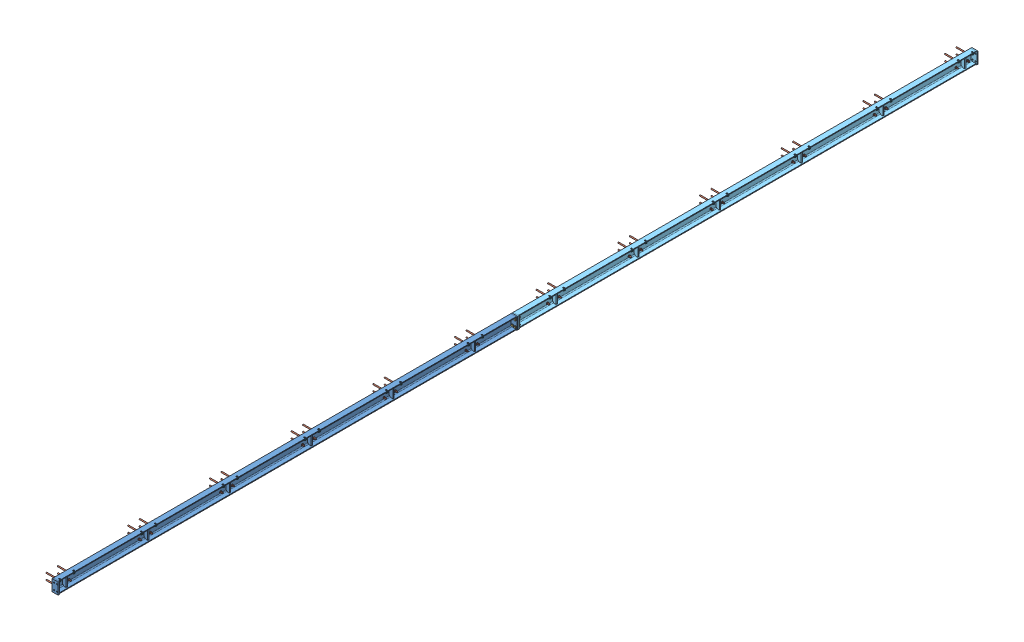
SolidWorks assembly 0405-WALL ASSEMBLAGE, configuration Predeterminado. Lengths in mm.
Overall size (203.98 166 11260).
106 component instances, 7 part files, 35 mates.
Components (placement in the parent):
- 0418-WALL SUPPORT-1: 0418-WALL SUPPORT [Predeterminado] at (-23.835 3.2677 -2786.25) size (75 140 5630)
- M-12x160 CHEMICAL ANCHOR-1: M-12x160 CHEMICAL ANCHOR [DIN 525 - M20 x 210 --- 75N] at (-150.835 41.2677 2769.75) x (1 0 0) z (0 -0.732552 0.680711) size (160 24 24)
- M-12x160 CHEMICAL ANCHOR-31: M-12x160 CHEMICAL ANCHOR [DIN 525 - M20 x 210 --- 75N] at (-150.835 -34.7323 2769.75) x (1 0 0) z (0 -0.732552 0.680711) size (160 24 24)
- M-12x160 CHEMICAL ANCHOR-49: M-12x160 CHEMICAL ANCHOR [DIN 525 - M20 x 210 --- 75N] at (-150.835 41.2677 2629.75) x (1 0 0) z (0 -0.732552 0.680711) size (160 24 24)
- M-12x160 CHEMICAL ANCHOR-61: M-12x160 CHEMICAL ANCHOR [DIN 525 - M20 x 210 --- 75N] at (-150.835 -34.7323 2629.75) x (1 0 0) z (0 -0.732552 0.680711) size (160 24 24)
- M-12x160 CHEMICAL ANCHOR-32: M-12x160 CHEMICAL ANCHOR [DIN 525 - M20 x 210 --- 75N] at (-150.835 -34.7323 1769.75) x (1 0 0) z (0 -0.732552 0.680711) size (160 24 24)
- M-12x160 CHEMICAL ANCHOR-33: M-12x160 CHEMICAL ANCHOR [DIN 525 - M20 x 210 --- 75N] at (-150.835 -34.7323 769.75) x (1 0 0) z (0 -0.732552 0.680711) size (160 24 24)
- M-12x160 CHEMICAL ANCHOR-34: M-12x160 CHEMICAL ANCHOR [DIN 525 - M20 x 210 --- 75N] at (-150.835 -34.7323 -230.25) x (1 0 0) z (0 -0.732552 0.680711) size (160 24 24)
- M-12x160 CHEMICAL ANCHOR-35: M-12x160 CHEMICAL ANCHOR [DIN 525 - M20 x 210 --- 75N] at (-150.835 -34.7323 -1230.25) x (1 0 0) z (0 -0.732552 0.680711) size (160 24 24)
- M-12x160 CHEMICAL ANCHOR-36: M-12x160 CHEMICAL ANCHOR [DIN 525 - M20 x 210 --- 75N] at (-150.835 -34.7323 -2230.25) x (1 0 0) z (0 -0.732552 0.680711) size (160 24 24)
- M-12x160 CHEMICAL ANCHOR-62: M-12x160 CHEMICAL ANCHOR [DIN 525 - M20 x 210 --- 75N] at (-150.835 -34.7323 1629.75) x (1 0 0) z (0 -0.732552 0.680711) size (160 24 24)
- M-12x160 CHEMICAL ANCHOR-63: M-12x160 CHEMICAL ANCHOR [DIN 525 - M20 x 210 --- 75N] at (-150.835 -34.7323 629.75) x (1 0 0) z (0 -0.732552 0.680711) size (160 24 24)
- M-12x160 CHEMICAL ANCHOR-64: M-12x160 CHEMICAL ANCHOR [DIN 525 - M20 x 210 --- 75N] at (-150.835 -34.7323 -370.25) x (1 0 0) z (0 -0.732552 0.680711) size (160 24 24)
- M-12x160 CHEMICAL ANCHOR-65: M-12x160 CHEMICAL ANCHOR [DIN 525 - M20 x 210 --- 75N] at (-150.835 -34.7323 -1370.25) x (1 0 0) z (0 -0.732552 0.680711) size (160 24 24)
- M-12x160 CHEMICAL ANCHOR-66: M-12x160 CHEMICAL ANCHOR [DIN 525 - M20 x 210 --- 75N] at (-150.835 -34.7323 -2370.25) x (1 0 0) z (0 -0.732552 0.680711) size (160 24 24)
- M-12x160 CHEMICAL ANCHOR-50: M-12x160 CHEMICAL ANCHOR [DIN 525 - M20 x 210 --- 75N] at (-150.835 41.2677 1629.75) x (1 0 0) z (0 -0.732552 0.680711) size (160 24 24)
- M-12x160 CHEMICAL ANCHOR-51: M-12x160 CHEMICAL ANCHOR [DIN 525 - M20 x 210 --- 75N] at (-150.835 41.2677 629.75) x (1 0 0) z (0 -0.732552 0.680711) size (160 24 24)
- M-12x160 CHEMICAL ANCHOR-52: M-12x160 CHEMICAL ANCHOR [DIN 525 - M20 x 210 --- 75N] at (-150.835 41.2677 -370.25) x (1 0 0) z (0 -0.732552 0.680711) size (160 24 24)
- M-12x160 CHEMICAL ANCHOR-53: M-12x160 CHEMICAL ANCHOR [DIN 525 - M20 x 210 --- 75N] at (-150.835 41.2677 -1370.25) x (1 0 0) z (0 -0.732552 0.680711) size (160 24 24)
- M-12x160 CHEMICAL ANCHOR-54: M-12x160 CHEMICAL ANCHOR [DIN 525 - M20 x 210 --- 75N] at (-150.835 41.2677 -2370.25) x (1 0 0) z (0 -0.732552 0.680711) size (160 24 24)
- M-12x160 CHEMICAL ANCHOR-20: M-12x160 CHEMICAL ANCHOR [DIN 525 - M20 x 210 --- 75N] at (-150.835 41.2677 1769.75) x (1 0 0) z (0 -0.732552 0.680711) size (160 24 24)
- M-12x160 CHEMICAL ANCHOR-21: M-12x160 CHEMICAL ANCHOR [DIN 525 - M20 x 210 --- 75N] at (-150.835 41.2677 769.75) x (1 0 0) z (0 -0.732552 0.680711) size (160 24 24)
- M-12x160 CHEMICAL ANCHOR-22: M-12x160 CHEMICAL ANCHOR [DIN 525 - M20 x 210 --- 75N] at (-150.835 41.2677 -230.25) x (1 0 0) z (0 -0.732552 0.680711) size (160 24 24)
- M-12x160 CHEMICAL ANCHOR-23: M-12x160 CHEMICAL ANCHOR [DIN 525 - M20 x 210 --- 75N] at (-150.835 41.2677 -1230.25) x (1 0 0) z (0 -0.732552 0.680711) size (160 24 24)
- M-12x160 CHEMICAL ANCHOR-24: M-12x160 CHEMICAL ANCHOR [DIN 525 - M20 x 210 --- 75N] at (-150.835 41.2677 -2230.25) x (1 0 0) z (0 -0.732552 0.680711) size (160 24 24)
- M-12x55 DIN-6914-18 and DIN-6916-1: M-12x55 DIN-6914-18 and DIN-6916 [DIN 6914 - M12 x 35 x 21-N] at (1.165 43.2677 -2776.25) x (0 0 -1) z (0.381849 -0.924225 0) size (63 26 26)
- M-12x55 DIN-6914-18 and DIN-6916-2: M-12x55 DIN-6914-18 and DIN-6916 [DIN 6914 - M12 x 35 x 21-N] at (36.165 43.2677 -2776.25) x (0 0 -1) z (0.381849 -0.924225 0) size (63 26 26)
- M-12x55 DIN-6914-18 and DIN-6916-3: M-12x55 DIN-6914-18 and DIN-6916 [DIN 6914 - M12 x 35 x 21-N] at (1.165 -36.7323 -2776.25) x (0 0 -1) z (0.381849 -0.924225 0) size (63 26 26)
- M-12x55 DIN-6914-18 and DIN-6916-4: M-12x55 DIN-6914-18 and DIN-6916 [DIN 6914 - M12 x 35 x 21-N] at (36.165 -36.7323 -2776.25) x (0 0 -1) z (0.381849 -0.924225 0) size (63 26 26)
- M-12 DIN-6915 and DIN-6916-1: M-12 DIN-6915 and DIN-6916 [Hexagon Nut DIN 6915 - M12 - N] at (1.165 43.2677 -2818.25) size (26 26 12)
- M-12 DIN-6915 and DIN-6916-2: M-12 DIN-6915 and DIN-6916 [Hexagon Nut DIN 6915 - M12 - N] at (36.165 43.2677 -2818.25) size (26 26 12)
- M-12 DIN-6915 and DIN-6916-3: M-12 DIN-6915 and DIN-6916 [Hexagon Nut DIN 6915 - M12 - N] at (36.165 -36.7323 -2818.25) size (26 26 12)
- M-12 DIN-6915 and DIN-6916-4: M-12 DIN-6915 and DIN-6916 [Hexagon Nut DIN 6915 - M12 - N] at (1.165 -36.7323 -2818.25) size (26 26 12)
- 0419-WALL SUPPORT-1: 0419-WALL SUPPORT [Predeterminado] at (-23.835 3.2677 -2816.25) x (1 0 0) z (0 0 -1) size (75 140 5630)
- M-12x160 CHEMICAL ANCHOR-25: M-12x160 CHEMICAL ANCHOR [DIN 525 - M20 x 210 --- 75N] at (-150.835 41.2677 -3230.25) x (1 0 0) z (0 -0.732552 0.680711) size (160 24 24)
- M-12x160 CHEMICAL ANCHOR-26: M-12x160 CHEMICAL ANCHOR [DIN 525 - M20 x 210 --- 75N] at (-150.835 41.2677 -4230.25) x (1 0 0) z (0 -0.732552 0.680711) size (160 24 24)
- M-12x160 CHEMICAL ANCHOR-27: M-12x160 CHEMICAL ANCHOR [DIN 525 - M20 x 210 --- 75N] at (-150.835 41.2677 -5230.25) x (1 0 0) z (0 -0.732552 0.680711) size (160 24 24)
- M-12x160 CHEMICAL ANCHOR-28: M-12x160 CHEMICAL ANCHOR [DIN 525 - M20 x 210 --- 75N] at (-150.835 41.2677 -6230.25) x (1 0 0) z (0 -0.732552 0.680711) size (160 24 24)
- M-12x160 CHEMICAL ANCHOR-29: M-12x160 CHEMICAL ANCHOR [DIN 525 - M20 x 210 --- 75N] at (-150.835 41.2677 -7230.25) x (1 0 0) z (0 -0.732552 0.680711) size (160 24 24)
- M-12x160 CHEMICAL ANCHOR-30: M-12x160 CHEMICAL ANCHOR [DIN 525 - M20 x 210 --- 75N] at (-150.835 41.2677 -8230.25) x (1 0 0) z (0 -0.732552 0.680711) size (160 24 24)
- M-12x160 CHEMICAL ANCHOR-55: M-12x160 CHEMICAL ANCHOR [DIN 525 - M20 x 210 --- 75N] at (-150.835 41.2677 -3370.25) x (1 0 0) z (0 -0.732552 0.680711) size (160 24 24)
- M-12x160 CHEMICAL ANCHOR-56: M-12x160 CHEMICAL ANCHOR [DIN 525 - M20 x 210 --- 75N] at (-150.835 41.2677 -4370.25) x (1 0 0) z (0 -0.732552 0.680711) size (160 24 24)
- M-12x160 CHEMICAL ANCHOR-57: M-12x160 CHEMICAL ANCHOR [DIN 525 - M20 x 210 --- 75N] at (-150.835 41.2677 -5370.25) x (1 0 0) z (0 -0.732552 0.680711) size (160 24 24)
- M-12x160 CHEMICAL ANCHOR-58: M-12x160 CHEMICAL ANCHOR [DIN 525 - M20 x 210 --- 75N] at (-150.835 41.2677 -6370.25) x (1 0 0) z (0 -0.732552 0.680711) size (160 24 24)
- M-12x160 CHEMICAL ANCHOR-59: M-12x160 CHEMICAL ANCHOR [DIN 525 - M20 x 210 --- 75N] at (-150.835 41.2677 -7370.25) x (1 0 0) z (0 -0.732552 0.680711) size (160 24 24)
- M-12x160 CHEMICAL ANCHOR-60: M-12x160 CHEMICAL ANCHOR [DIN 525 - M20 x 210 --- 75N] at (-150.835 41.2677 -8370.25) x (1 0 0) z (0 -0.732552 0.680711) size (160 24 24)
- M-12x160 CHEMICAL ANCHOR-67: M-12x160 CHEMICAL ANCHOR [DIN 525 - M20 x 210 --- 75N] at (-150.835 -34.7323 -3370.25) x (1 0 0) z (0 -0.732552 0.680711) size (160 24 24)
- M-12x160 CHEMICAL ANCHOR-68: M-12x160 CHEMICAL ANCHOR [DIN 525 - M20 x 210 --- 75N] at (-150.835 -34.7323 -4370.25) x (1 0 0) z (0 -0.732552 0.680711) size (160 24 24)
- M-12x160 CHEMICAL ANCHOR-69: M-12x160 CHEMICAL ANCHOR [DIN 525 - M20 x 210 --- 75N] at (-150.835 -34.7323 -5370.25) x (1 0 0) z (0 -0.732552 0.680711) size (160 24 24)
- M-12x160 CHEMICAL ANCHOR-70: M-12x160 CHEMICAL ANCHOR [DIN 525 - M20 x 210 --- 75N] at (-150.835 -34.7323 -6370.25) x (1 0 0) z (0 -0.732552 0.680711) size (160 24 24)
- M-12x160 CHEMICAL ANCHOR-71: M-12x160 CHEMICAL ANCHOR [DIN 525 - M20 x 210 --- 75N] at (-150.835 -34.7323 -7370.25) x (1 0 0) z (0 -0.732552 0.680711) size (160 24 24)
- M-12x160 CHEMICAL ANCHOR-72: M-12x160 CHEMICAL ANCHOR [DIN 525 - M20 x 210 --- 75N] at (-150.835 -34.7323 -8370.25) x (1 0 0) z (0 -0.732552 0.680711) size (160 24 24)
- M-12x160 CHEMICAL ANCHOR-43: M-12x160 CHEMICAL ANCHOR [DIN 525 - M20 x 210 --- 75N] at (-150.835 -34.7323 -3230.25) x (1 0 0) z (0 -0.732552 0.680711) size (160 24 24)
- M-12x160 CHEMICAL ANCHOR-44: M-12x160 CHEMICAL ANCHOR [DIN 525 - M20 x 210 --- 75N] at (-150.835 -34.7323 -4230.25) x (1 0 0) z (0 -0.732552 0.680711) size (160 24 24)
- M-12x160 CHEMICAL ANCHOR-45: M-12x160 CHEMICAL ANCHOR [DIN 525 - M20 x 210 --- 75N] at (-150.835 -34.7323 -5230.25) x (1 0 0) z (0 -0.732552 0.680711) size (160 24 24)
- M-12x160 CHEMICAL ANCHOR-46: M-12x160 CHEMICAL ANCHOR [DIN 525 - M20 x 210 --- 75N] at (-150.835 -34.7323 -6230.25) x (1 0 0) z (0 -0.732552 0.680711) size (160 24 24)
- M-12x160 CHEMICAL ANCHOR-47: M-12x160 CHEMICAL ANCHOR [DIN 525 - M20 x 210 --- 75N] at (-150.835 -34.7323 -7230.25) x (1 0 0) z (0 -0.732552 0.680711) size (160 24 24)
- M-12x160 CHEMICAL ANCHOR-48: M-12x160 CHEMICAL ANCHOR [DIN 525 - M20 x 210 --- 75N] at (-150.835 -34.7323 -8230.25) x (1 0 0) z (0 -0.732552 0.680711) size (160 24 24)
- M-16x45 DIN-6914-18 and DIN-6916-1: M-16x45 DIN-6914-18 and DIN-6916 [DIN 6914 - M20 x 65 x 31-N] at (26.165 99.2677 2785.75) x (0 -1 0) z (0 0 1) size (58 30 30)
- M-16x45 DIN-6914-18 and DIN-6916-25: M-16x45 DIN-6914-18 and DIN-6916 [DIN 6914 - M20 x 65 x 31-N] at (26.165 99.2677 2613.75) x (0 -1 0) z (0 0 1) size (58 30 30)
- M-16 DIN-6915 and DIN-6916-1: M-16 DIN-6915 and DIN-6916 [Hexagon Nut DIN 6915 - M20 - N] at (26.165 61.2677 2785.75) x (1 0 0) z (0 1 0) size (30 30 16)
- M-16 DIN-6915 and DIN-6916-2: M-16 DIN-6915 and DIN-6916 [Hexagon Nut DIN 6915 - M20 - N] at (26.165 61.2677 2613.75) x (1 0 0) z (0 1 0) size (30 30 16)
- M-16 DIN-6915 and DIN-6916-3: M-16 DIN-6915 and DIN-6916 [Hexagon Nut DIN 6915 - M20 - N] at (26.165 61.2677 1785.75) x (1 0 0) z (0 1 0) size (30 30 16)
- M-16 DIN-6915 and DIN-6916-4: M-16 DIN-6915 and DIN-6916 [Hexagon Nut DIN 6915 - M20 - N] at (26.165 61.2677 785.75) x (1 0 0) z (0 1 0) size (30 30 16)
- M-16 DIN-6915 and DIN-6916-5: M-16 DIN-6915 and DIN-6916 [Hexagon Nut DIN 6915 - M20 - N] at (26.165 61.2677 -214.25) x (1 0 0) z (0 1 0) size (30 30 16)
- M-16 DIN-6915 and DIN-6916-6: M-16 DIN-6915 and DIN-6916 [Hexagon Nut DIN 6915 - M20 - N] at (26.165 61.2677 -1214.25) x (1 0 0) z (0 1 0) size (30 30 16)
- M-16 DIN-6915 and DIN-6916-7: M-16 DIN-6915 and DIN-6916 [Hexagon Nut DIN 6915 - M20 - N] at (26.165 61.2677 -2214.25) x (1 0 0) z (0 1 0) size (30 30 16)
- M-16 DIN-6915 and DIN-6916-8: M-16 DIN-6915 and DIN-6916 [Hexagon Nut DIN 6915 - M20 - N] at (26.165 61.2677 -3214.25) x (1 0 0) z (0 1 0) size (30 30 16)
- M-16 DIN-6915 and DIN-6916-9: M-16 DIN-6915 and DIN-6916 [Hexagon Nut DIN 6915 - M20 - N] at (26.165 61.2677 -4214.25) x (1 0 0) z (0 1 0) size (30 30 16)
- M-16 DIN-6915 and DIN-6916-10: M-16 DIN-6915 and DIN-6916 [Hexagon Nut DIN 6915 - M20 - N] at (26.165 61.2677 -5214.25) x (1 0 0) z (0 1 0) size (30 30 16)
- M-16 DIN-6915 and DIN-6916-11: M-16 DIN-6915 and DIN-6916 [Hexagon Nut DIN 6915 - M20 - N] at (26.165 61.2677 -6214.25) x (1 0 0) z (0 1 0) size (30 30 16)
- M-16 DIN-6915 and DIN-6916-12: M-16 DIN-6915 and DIN-6916 [Hexagon Nut DIN 6915 - M20 - N] at (26.165 61.2677 -7214.25) x (1 0 0) z (0 1 0) size (30 30 16)
- M-16 DIN-6915 and DIN-6916-13: M-16 DIN-6915 and DIN-6916 [Hexagon Nut DIN 6915 - M20 - N] at (26.165 61.2677 -8214.25) x (1 0 0) z (0 1 0) size (30 30 16)
- M-16 DIN-6915 and DIN-6916-14: M-16 DIN-6915 and DIN-6916 [Hexagon Nut DIN 6915 - M20 - N] at (26.165 61.2677 1613.75) x (1 0 0) z (0 1 0) size (30 30 16)
- M-16 DIN-6915 and DIN-6916-15: M-16 DIN-6915 and DIN-6916 [Hexagon Nut DIN 6915 - M20 - N] at (26.165 61.2677 613.75) x (1 0 0) z (0 1 0) size (30 30 16)
- M-16 DIN-6915 and DIN-6916-16: M-16 DIN-6915 and DIN-6916 [Hexagon Nut DIN 6915 - M20 - N] at (26.165 61.2677 -386.25) x (1 0 0) z (0 1 0) size (30 30 16)
- M-16 DIN-6915 and DIN-6916-17: M-16 DIN-6915 and DIN-6916 [Hexagon Nut DIN 6915 - M20 - N] at (26.165 61.2677 -1386.25) x (1 0 0) z (0 1 0) size (30 30 16)
- M-16 DIN-6915 and DIN-6916-18: M-16 DIN-6915 and DIN-6916 [Hexagon Nut DIN 6915 - M20 - N] at (26.165 61.2677 -2386.25) x (1 0 0) z (0 1 0) size (30 30 16)
- M-16 DIN-6915 and DIN-6916-19: M-16 DIN-6915 and DIN-6916 [Hexagon Nut DIN 6915 - M20 - N] at (26.165 61.2677 -3386.25) x (1 0 0) z (0 1 0) size (30 30 16)
- M-16 DIN-6915 and DIN-6916-20: M-16 DIN-6915 and DIN-6916 [Hexagon Nut DIN 6915 - M20 - N] at (26.165 61.2677 -4386.25) x (1 0 0) z (0 1 0) size (30 30 16)
- M-16 DIN-6915 and DIN-6916-21: M-16 DIN-6915 and DIN-6916 [Hexagon Nut DIN 6915 - M20 - N] at (26.165 61.2677 -5386.25) x (1 0 0) z (0 1 0) size (30 30 16)
- M-16 DIN-6915 and DIN-6916-22: M-16 DIN-6915 and DIN-6916 [Hexagon Nut DIN 6915 - M20 - N] at (26.165 61.2677 -6386.25) x (1 0 0) z (0 1 0) size (30 30 16)
- M-16 DIN-6915 and DIN-6916-23: M-16 DIN-6915 and DIN-6916 [Hexagon Nut DIN 6915 - M20 - N] at (26.165 61.2677 -7386.25) x (1 0 0) z (0 1 0) size (30 30 16)
- M-16 DIN-6915 and DIN-6916-24: M-16 DIN-6915 and DIN-6916 [Hexagon Nut DIN 6915 - M20 - N] at (26.165 61.2677 -8386.25) x (1 0 0) z (0 1 0) size (30 30 16)
- M-16x45 DIN-6914-18 and DIN-6916-26: M-16x45 DIN-6914-18 and DIN-6916 [DIN 6914 - M20 x 65 x 31-N] at (26.165 99.2677 1613.75) x (0 -1 0) z (0 0 1) size (58 30 30)
- M-16x45 DIN-6914-18 and DIN-6916-27: M-16x45 DIN-6914-18 and DIN-6916 [DIN 6914 - M20 x 65 x 31-N] at (26.165 99.2677 613.75) x (0 -1 0) z (0 0 1) size (58 30 30)
- M-16x45 DIN-6914-18 and DIN-6916-28: M-16x45 DIN-6914-18 and DIN-6916 [DIN 6914 - M20 x 65 x 31-N] at (26.165 99.2677 -386.25) x (0 -1 0) z (0 0 1) size (58 30 30)
- M-16x45 DIN-6914-18 and DIN-6916-29: M-16x45 DIN-6914-18 and DIN-6916 [DIN 6914 - M20 x 65 x 31-N] at (26.165 99.2677 -1386.25) x (0 -1 0) z (0 0 1) size (58 30 30)
- M-16x45 DIN-6914-18 and DIN-6916-30: M-16x45 DIN-6914-18 and DIN-6916 [DIN 6914 - M20 x 65 x 31-N] at (26.165 99.2677 -2386.25) x (0 -1 0) z (0 0 1) size (58 30 30)
- M-16x45 DIN-6914-18 and DIN-6916-31: M-16x45 DIN-6914-18 and DIN-6916 [DIN 6914 - M20 x 65 x 31-N] at (26.165 99.2677 -3386.25) x (0 -1 0) z (0 0 1) size (58 30 30)
- M-16x45 DIN-6914-18 and DIN-6916-32: M-16x45 DIN-6914-18 and DIN-6916 [DIN 6914 - M20 x 65 x 31-N] at (26.165 99.2677 -4386.25) x (0 -1 0) z (0 0 1) size (58 30 30)
- M-16x45 DIN-6914-18 and DIN-6916-33: M-16x45 DIN-6914-18 and DIN-6916 [DIN 6914 - M20 x 65 x 31-N] at (26.165 99.2677 -5386.25) x (0 -1 0) z (0 0 1) size (58 30 30)
- M-16x45 DIN-6914-18 and DIN-6916-34: M-16x45 DIN-6914-18 and DIN-6916 [DIN 6914 - M20 x 65 x 31-N] at (26.165 99.2677 -6386.25) x (0 -1 0) z (0 0 1) size (58 30 30)
- M-16x45 DIN-6914-18 and DIN-6916-35: M-16x45 DIN-6914-18 and DIN-6916 [DIN 6914 - M20 x 65 x 31-N] at (26.165 99.2677 -7386.25) x (0 -1 0) z (0 0 1) size (58 30 30)
- M-16x45 DIN-6914-18 and DIN-6916-36: M-16x45 DIN-6914-18 and DIN-6916 [DIN 6914 - M20 x 65 x 31-N] at (26.165 99.2677 -8386.25) x (0 -1 0) z (0 0 1) size (58 30 30)
- M-16x45 DIN-6914-18 and DIN-6916-14: M-16x45 DIN-6914-18 and DIN-6916 [DIN 6914 - M20 x 65 x 31-N] at (26.165 99.2677 1785.75) x (0 -1 0) z (0 0 1) size (58 30 30)
- M-16x45 DIN-6914-18 and DIN-6916-15: M-16x45 DIN-6914-18 and DIN-6916 [DIN 6914 - M20 x 65 x 31-N] at (26.165 99.2677 785.75) x (0 -1 0) z (0 0 1) size (58 30 30)
- M-16x45 DIN-6914-18 and DIN-6916-16: M-16x45 DIN-6914-18 and DIN-6916 [DIN 6914 - M20 x 65 x 31-N] at (26.165 99.2677 -214.25) x (0 -1 0) z (0 0 1) size (58 30 30)
- M-16x45 DIN-6914-18 and DIN-6916-17: M-16x45 DIN-6914-18 and DIN-6916 [DIN 6914 - M20 x 65 x 31-N] at (26.165 99.2677 -1214.25) x (0 -1 0) z (0 0 1) size (58 30 30)
- M-16x45 DIN-6914-18 and DIN-6916-18: M-16x45 DIN-6914-18 and DIN-6916 [DIN 6914 - M20 x 65 x 31-N] at (26.165 99.2677 -2214.25) x (0 -1 0) z (0 0 1) size (58 30 30)
- M-16x45 DIN-6914-18 and DIN-6916-19: M-16x45 DIN-6914-18 and DIN-6916 [DIN 6914 - M20 x 65 x 31-N] at (26.165 99.2677 -3214.25) x (0 -1 0) z (0 0 1) size (58 30 30)
- M-16x45 DIN-6914-18 and DIN-6916-20: M-16x45 DIN-6914-18 and DIN-6916 [DIN 6914 - M20 x 65 x 31-N] at (26.165 99.2677 -4214.25) x (0 -1 0) z (0 0 1) size (58 30 30)
- M-16x45 DIN-6914-18 and DIN-6916-21: M-16x45 DIN-6914-18 and DIN-6916 [DIN 6914 - M20 x 65 x 31-N] at (26.165 99.2677 -5214.25) x (0 -1 0) z (0 0 1) size (58 30 30)
- M-16x45 DIN-6914-18 and DIN-6916-22: M-16x45 DIN-6914-18 and DIN-6916 [DIN 6914 - M20 x 65 x 31-N] at (26.165 99.2677 -6214.25) x (0 -1 0) z (0 0 1) size (58 30 30)
- M-16x45 DIN-6914-18 and DIN-6916-23: M-16x45 DIN-6914-18 and DIN-6916 [DIN 6914 - M20 x 65 x 31-N] at (26.165 99.2677 -7214.25) x (0 -1 0) z (0 0 1) size (58 30 30)
- M-16x45 DIN-6914-18 and DIN-6916-24: M-16x45 DIN-6914-18 and DIN-6916 [DIN 6914 - M20 x 65 x 31-N] at (26.165 99.2677 -8214.25) x (0 -1 0) z (0 0 1) size (58 30 30)
Mates (geometry in assembly coordinates):
- Concéntrica1: concentric aligned: cylinder of 0418-WALL SUPPORT-1 through (51.166 41.2677 2769.75) axis (-1 0 0) radius 7; cylinder of M-12x160 CHEMICAL ANCHOR-1 through (-182.585 41.2677 2769.75) axis (-1 0 0) radius 6
- Coincidente2: coincident anti-aligned: plane of 0418-WALL SUPPORT-1 through (-18.835 -45.7323 2813.75) normal (1 0 0); plane of M-12x160 CHEMICAL ANCHOR-1 through (-18.835 41.2677 2769.75) normal (-1 0 0)
- Concéntrica2: concentric aligned: cylinder of 0418-WALL SUPPORT-1 through (51.166 -34.7323 2769.75) axis (-1 0 0) radius 7; cylinder of M-12x160 CHEMICAL ANCHOR-31 through (-182.585 -34.7323 2769.75) axis (-1 0 0) radius 6
- Coincidente3: coincident anti-aligned: plane of 0418-WALL SUPPORT-1 through (-18.835 -45.7323 2813.75) normal (1 0 0); plane of M-12x160 CHEMICAL ANCHOR-31 through (-18.835 -34.7323 2769.75) normal (-1 0 0)
- Concéntrica3: concentric aligned: cylinder of 0418-WALL SUPPORT-1 through (51.166 41.2677 2629.75) axis (-1 0 0) radius 7; cylinder of M-12x160 CHEMICAL ANCHOR-49 through (-182.585 41.2677 2629.75) axis (-1 0 0) radius 6
- Coincidente4: coincident anti-aligned: plane of 0418-WALL SUPPORT-1 through (-18.835 -45.7323 2813.75) normal (1 0 0); plane of M-12x160 CHEMICAL ANCHOR-49 through (-18.835 41.2677 2629.75) normal (-1 0 0)
- Concéntrica4: concentric aligned: cylinder of 0418-WALL SUPPORT-1 through (51.166 -34.7323 2629.75) axis (-1 0 0) radius 7; cylinder of M-12x160 CHEMICAL ANCHOR-61 through (-182.585 -34.7323 2629.75) axis (-1 0 0) radius 6
- Coincidente5: coincident anti-aligned: plane of 0418-WALL SUPPORT-1 through (-18.835 -45.7323 2813.75) normal (1 0 0); plane of M-12x160 CHEMICAL ANCHOR-61 through (-18.835 -34.7323 2629.75) normal (-1 0 0)
- Coincidente6: coincident anti-aligned: plane of 0418-WALL SUPPORT-1 through (-23.835 -66.7323 -2801.25) normal (0 0 -1); plane of 0419-WALL SUPPORT-1 through (-23.835 73.2677 -2801.25) normal (0 0 1)
- Coincidente7: coincident aligned: plane of 0418-WALL SUPPORT-1 through (41.165 73.2677 2813.75) normal (0 1 0); plane of 0419-WALL SUPPORT-1 through (-23.835 73.2677 -8416.25) normal (0 1 0)
- Coincidente8: coincident aligned: plane of 0418-WALL SUPPORT-1 through (-23.835 73.2677 2813.75) normal (-1 0 0); plane of 0419-WALL SUPPORT-1 through (-23.835 -66.7323 -8416.25) normal (-1 0 0)
- Coincidente10: coincident anti-aligned: plane of 0418-WALL SUPPORT-1 through (-23.835 -66.7323 -2786.25) normal (0 0 1); plane of M-12x55 DIN-6914-18 and DIN-6916-1 through (1.165 43.2677 -2786.25) normal (0 0 -1)
- Concéntrica6: concentric anti-aligned: cylinder of 0418-WALL SUPPORT-1 through (1.165 43.2677 -2766.451) axis (0 0 -1) radius 7; cylinder of M-12x55 DIN-6914-18 and DIN-6916-1 through (1.165 43.2677 -2776.25) axis (0 0 1) radius 6
- Coincidente11: coincident anti-aligned: plane of 0418-WALL SUPPORT-1 through (-23.835 -66.7323 -2786.25) normal (0 0 1); plane of M-12x55 DIN-6914-18 and DIN-6916-2 through (36.165 43.2677 -2786.25) normal (0 0 -1)
- Concéntrica7: concentric anti-aligned: cylinder of 0418-WALL SUPPORT-1 through (36.165 43.2677 -2766.451) axis (0 0 -1) radius 7; cylinder of M-12x55 DIN-6914-18 and DIN-6916-2 through (36.165 43.2677 -2776.25) axis (0 0 1) radius 6
- Coincidente12: coincident anti-aligned: plane of 0418-WALL SUPPORT-1 through (-23.835 -66.7323 -2786.25) normal (0 0 1); plane of M-12x55 DIN-6914-18 and DIN-6916-3 through (1.165 -36.7323 -2786.25) normal (0 0 -1)
- Concéntrica8: concentric anti-aligned: cylinder of 0418-WALL SUPPORT-1 through (1.165 -36.7323 -2766.451) axis (0 0 -1) radius 7; cylinder of M-12x55 DIN-6914-18 and DIN-6916-3 through (1.165 -36.7323 -2776.25) axis (0 0 1) radius 6
- Coincidente13: coincident anti-aligned: plane of 0418-WALL SUPPORT-1 through (-23.835 -66.7323 -2786.25) normal (0 0 1); plane of M-12x55 DIN-6914-18 and DIN-6916-4 through (36.165 -36.7323 -2786.25) normal (0 0 -1)
- Concéntrica9: concentric anti-aligned: cylinder of 0418-WALL SUPPORT-1 through (36.165 -36.7323 -2766.451) axis (0 0 -1) radius 7; cylinder of M-12x55 DIN-6914-18 and DIN-6916-4 through (36.165 -36.7323 -2776.25) axis (0 0 1) radius 6
- Coincidente14: coincident anti-aligned: plane of 0419-WALL SUPPORT-1 through (-23.835 73.2677 -2816.25) normal (0 0 -1); plane of M-12 DIN-6915 and DIN-6916-1 through (1.165 43.2677 -2816.25) normal (0 0 1)
- Concéntrica10: concentric aligned: cylinder of M-12x55 DIN-6914-18 and DIN-6916-1 through (1.165 43.2677 -2776.25) axis (0 0 1) radius 6; cylinder of M-12 DIN-6915 and DIN-6916-1 through (1.165 43.2677 -2828.25) axis (0 0 1) radius 5.1
- Coincidente15: coincident anti-aligned: plane of 0419-WALL SUPPORT-1 through (-23.835 73.2677 -2816.25) normal (0 0 -1); plane of M-12 DIN-6915 and DIN-6916-2 through (36.165 43.2677 -2816.25) normal (0 0 1)
- Concéntrica11: concentric aligned: cylinder of M-12x55 DIN-6914-18 and DIN-6916-2 through (36.165 43.2677 -2776.25) axis (0 0 1) radius 6; cylinder of M-12 DIN-6915 and DIN-6916-2 through (36.165 43.2677 -2828.25) axis (0 0 1) radius 5.1
- Coincidente16: coincident anti-aligned: plane of 0419-WALL SUPPORT-1 through (-23.835 73.2677 -2816.25) normal (0 0 -1); plane of M-12 DIN-6915 and DIN-6916-3 through (36.165 -36.7323 -2816.25) normal (0 0 1)
- Concéntrica12: concentric aligned: cylinder of M-12x55 DIN-6914-18 and DIN-6916-4 through (36.165 -36.7323 -2776.25) axis (0 0 1) radius 6; cylinder of M-12 DIN-6915 and DIN-6916-3 through (36.165 -36.7323 -2828.25) axis (0 0 1) radius 5.1
- Coincidente17: coincident anti-aligned: plane of 0419-WALL SUPPORT-1 through (-23.835 73.2677 -2816.25) normal (0 0 -1); plane of M-12 DIN-6915 and DIN-6916-4 through (1.165 -36.7323 -2816.25) normal (0 0 1)
- Concéntrica13: concentric aligned: cylinder of M-12x55 DIN-6914-18 and DIN-6916-3 through (1.165 -36.7323 -2776.25) axis (0 0 1) radius 6; cylinder of M-12 DIN-6915 and DIN-6916-4 through (1.165 -36.7323 -2828.25) axis (0 0 1) radius 5.1
- Concéntrica14: concentric anti-aligned: cylinder of 0418-WALL SUPPORT-1 through (26.165 98.7236 2785.75) axis (0 -1 0) radius 9; cylinder of M-16x45 DIN-6914-18 and DIN-6916-1 through (26.165 99.2677 2785.75) axis (0 1 0) radius 8
- Distancia1: distance = 10 mm anti-aligned: plane of M-16x45 DIN-6914-18 and DIN-6916-1 through (26.165 83.2677 2785.75) normal (0 -1 0); plane of 0418-WALL SUPPORT-1 through (41.165 73.2677 2813.75) normal (0 1 0)
- Concéntrica15: concentric anti-aligned: cylinder of 0418-WALL SUPPORT-1 through (26.165 98.7236 2613.75) axis (0 -1 0) radius 9; cylinder of M-16x45 DIN-6914-18 and DIN-6916-25 through (26.165 99.2677 2613.75) axis (0 1 0) radius 8
- Distancia2: distance = 10 mm anti-aligned: plane of M-16x45 DIN-6914-18 and DIN-6916-25 through (26.165 83.2677 2613.75) normal (0 -1 0); plane of 0418-WALL SUPPORT-1 through (41.165 73.2677 2813.75) normal (0 1 0)
- Concéntrica16: concentric aligned: cylinder of M-16x45 DIN-6914-18 and DIN-6916-1 through (26.165 99.2677 2785.75) axis (0 1 0) radius 8; cylinder of M-16 DIN-6915 and DIN-6916-1 through (26.165 48.2677 2785.75) axis (0 1 0) radius 8
- Coincidente19: coincident anti-aligned: plane of 0418-WALL SUPPORT-1 through (-6.835 64.2677 2813.75) normal (0 -1 0); plane of M-16 DIN-6915 and DIN-6916-1 through (26.165 64.2677 2785.75) normal (0 1 0)
- Concéntrica17: concentric aligned: cylinder of M-16x45 DIN-6914-18 and DIN-6916-25 through (26.165 99.2677 2613.75) axis (0 1 0) radius 8; cylinder of M-16 DIN-6915 and DIN-6916-2 through (26.165 48.2677 2613.75) axis (0 1 0) radius 8
- Coincidente20: coincident anti-aligned: plane of 0418-WALL SUPPORT-1 through (-6.835 64.2677 2813.75) normal (0 -1 0); plane of M-16 DIN-6915 and DIN-6916-2 through (26.165 64.2677 2613.75) normal (0 1 0)
